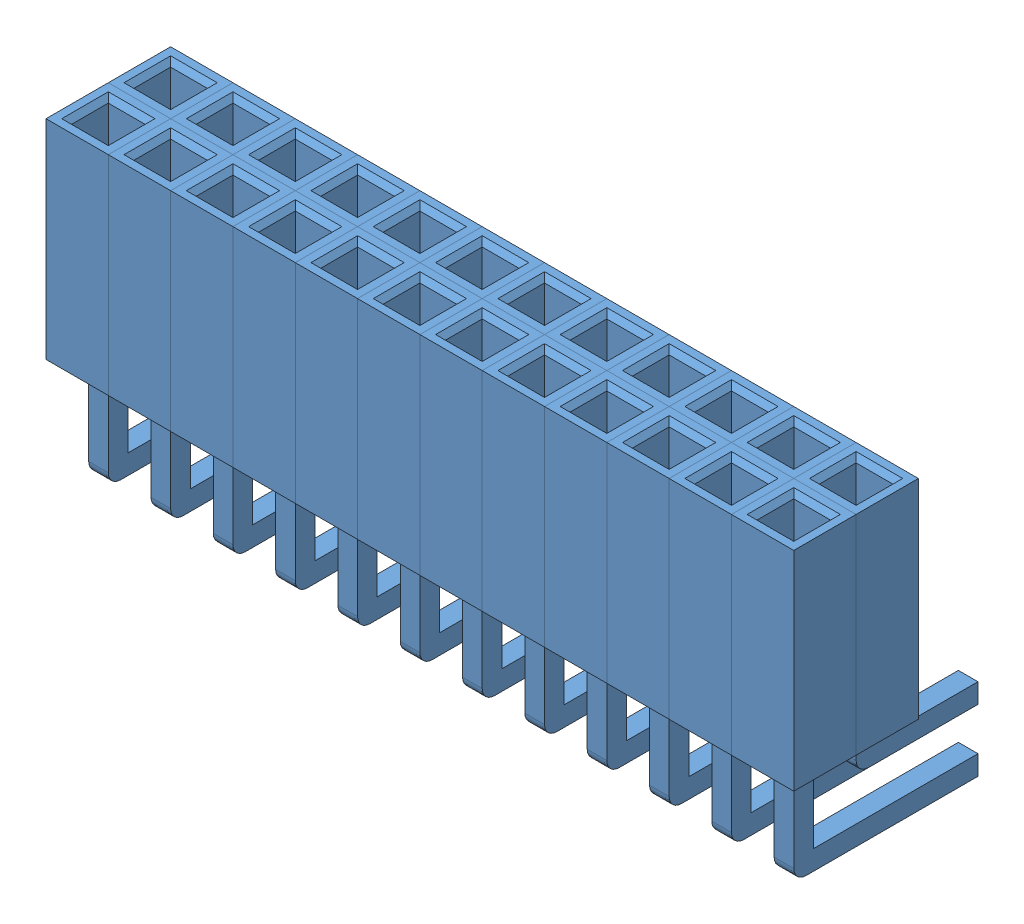
SolidWorks assembly pbd2x12, configuration По умолчанию. Lengths in mm.
Overall size (30.48 12.6 8.58).
28 component instances, 1 part files, 9 mates.
Components (placement in the parent):
- pbd2x3-1: pbd2x3 [По умолчанию] at (0.2433 0.0978 -4.4007) size (7.62 12.6 8.58)
  - PBS1-1: PBS1 [По умолчанию] at (-3.1437 -1.4395 4.583) size (2.54 10.06 6.04)
  - PBS1-2: PBS1 [По умолчанию] at (-0.6037 -1.4395 4.583) size (2.54 10.06 6.04)
  - PBS1-3: PBS1 [По умолчанию] at (1.9363 -1.4395 4.583) size (2.54 10.06 6.04)
  - PBS1-4: PBS1 [dowble] at (-3.1437 -1.4395 7.123) size (2.54 12.6 8.58)
  - PBS1-5: PBS1 [dowble] at (-0.6037 -1.4395 7.123) size (2.54 12.6 8.58)
  - PBS1-6: PBS1 [dowble] at (1.9363 -1.4395 7.123) size (2.54 12.6 8.58)
- pbd2x3-2: pbd2x3 [По умолчанию] at (-7.3767 0.0978 -4.4007) size (7.62 12.6 8.58)
  - PBS1-1: PBS1 [По умолчанию] at (-3.1437 -1.4395 4.583) size (2.54 10.06 6.04)
  - PBS1-2: PBS1 [По умолчанию] at (-0.6037 -1.4395 4.583) size (2.54 10.06 6.04)
  - PBS1-3: PBS1 [По умолчанию] at (1.9363 -1.4395 4.583) size (2.54 10.06 6.04)
  - PBS1-4: PBS1 [dowble] at (-3.1437 -1.4395 7.123) size (2.54 12.6 8.58)
  - PBS1-5: PBS1 [dowble] at (-0.6037 -1.4395 7.123) size (2.54 12.6 8.58)
  - PBS1-6: PBS1 [dowble] at (1.9363 -1.4395 7.123) size (2.54 12.6 8.58)
- pbd2x3-3: pbd2x3 [По умолчанию] at (-14.9967 0.0978 -4.4007) size (7.62 12.6 8.58)
  - PBS1-1: PBS1 [По умолчанию] at (-3.1437 -1.4395 4.583) size (2.54 10.06 6.04)
  - PBS1-2: PBS1 [По умолчанию] at (-0.6037 -1.4395 4.583) size (2.54 10.06 6.04)
  - PBS1-3: PBS1 [По умолчанию] at (1.9363 -1.4395 4.583) size (2.54 10.06 6.04)
  - PBS1-4: PBS1 [dowble] at (-3.1437 -1.4395 7.123) size (2.54 12.6 8.58)
  - PBS1-5: PBS1 [dowble] at (-0.6037 -1.4395 7.123) size (2.54 12.6 8.58)
  - PBS1-6: PBS1 [dowble] at (1.9363 -1.4395 7.123) size (2.54 12.6 8.58)
- pbd2x3-4: pbd2x3 [По умолчанию] at (7.8633 0.0978 -4.4007) size (7.62 12.6 8.58)
  - PBS1-1: PBS1 [По умолчанию] at (-3.1437 -1.4395 4.583) size (2.54 10.06 6.04)
  - PBS1-2: PBS1 [По умолчанию] at (-0.6037 -1.4395 4.583) size (2.54 10.06 6.04)
  - PBS1-3: PBS1 [По умолчанию] at (1.9363 -1.4395 4.583) size (2.54 10.06 6.04)
  - PBS1-4: PBS1 [dowble] at (-3.1437 -1.4395 7.123) size (2.54 12.6 8.58)
  - PBS1-5: PBS1 [dowble] at (-0.6037 -1.4395 7.123) size (2.54 12.6 8.58)
  - PBS1-6: PBS1 [dowble] at (1.9363 -1.4395 7.123) size (2.54 12.6 8.58)
Mates (geometry in assembly coordinates):
- Совпадение1: coincident aligned: plane of pbd2x3-1/PBS1-1 through (-2.9004 7.1583 -2.3578) normal (0 0 -1); plane of pbd2x3-2/PBS1-3 through (-5.4404 7.1583 -2.3578) normal (0 0 -1)
- Совпадение2: coincident aligned: plane of pbd2x3-1/PBS1-1 through (-2.9004 7.1583 0.1822) normal (0 1 0); plane of pbd2x3-2/PBS1-3 through (-5.4404 7.1583 0.1822) normal (0 1 0)
- Совпадение5: coincident anti-aligned: plane of pbd2x3-1/PBS1-1 through (-2.9004 7.1583 0.1822) normal (-1 0 0); plane of pbd2x3-2/PBS1-3 through (-2.9004 7.1583 0.1822) normal (1 0 0)
- Совпадение6: coincident anti-aligned: plane of pbd2x3-2/PBS1-1 through (-10.5204 7.1583 0.1822) normal (-1 0 0); plane of pbd2x3-3/PBS1-3 through (-10.5204 7.1583 0.1822) normal (1 0 0)
- Совпадение7: coincident aligned: plane of pbd2x3-2/PBS1-1 through (-10.5204 7.1583 -2.3578) normal (0 0 -1); plane of pbd2x3-3/PBS1-3 through (-13.0604 7.1583 -2.3578) normal (0 0 -1)
- Совпадение8: coincident aligned: plane of pbd2x3-2/PBS1-1 through (-10.5204 7.1583 0.1822) normal (0 1 0); plane of pbd2x3-3/PBS1-3 through (-13.0604 7.1583 0.1822) normal (0 1 0)
- Совпадение9: coincident anti-aligned: plane of pbd2x3-1/PBS1-3 through (4.7196 7.1583 0.1822) normal (1 0 0); plane of pbd2x3-4/PBS1-1 through (4.7196 7.1583 0.1822) normal (-1 0 0)
- Совпадение10: coincident aligned: plane of pbd2x3-1/PBS1-6 through (2.1796 7.1583 2.7222) normal (0 0 1); plane of pbd2x3-4/PBS1-4 through (4.7196 7.1583 2.7222) normal (0 0 1)
- Совпадение11: coincident aligned: plane of pbd2x3-1/PBS1-6 through (2.1796 7.1583 2.7222) normal (0 1 0); plane of pbd2x3-4/PBS1-4 through (4.7196 7.1583 2.7222) normal (0 1 0)
